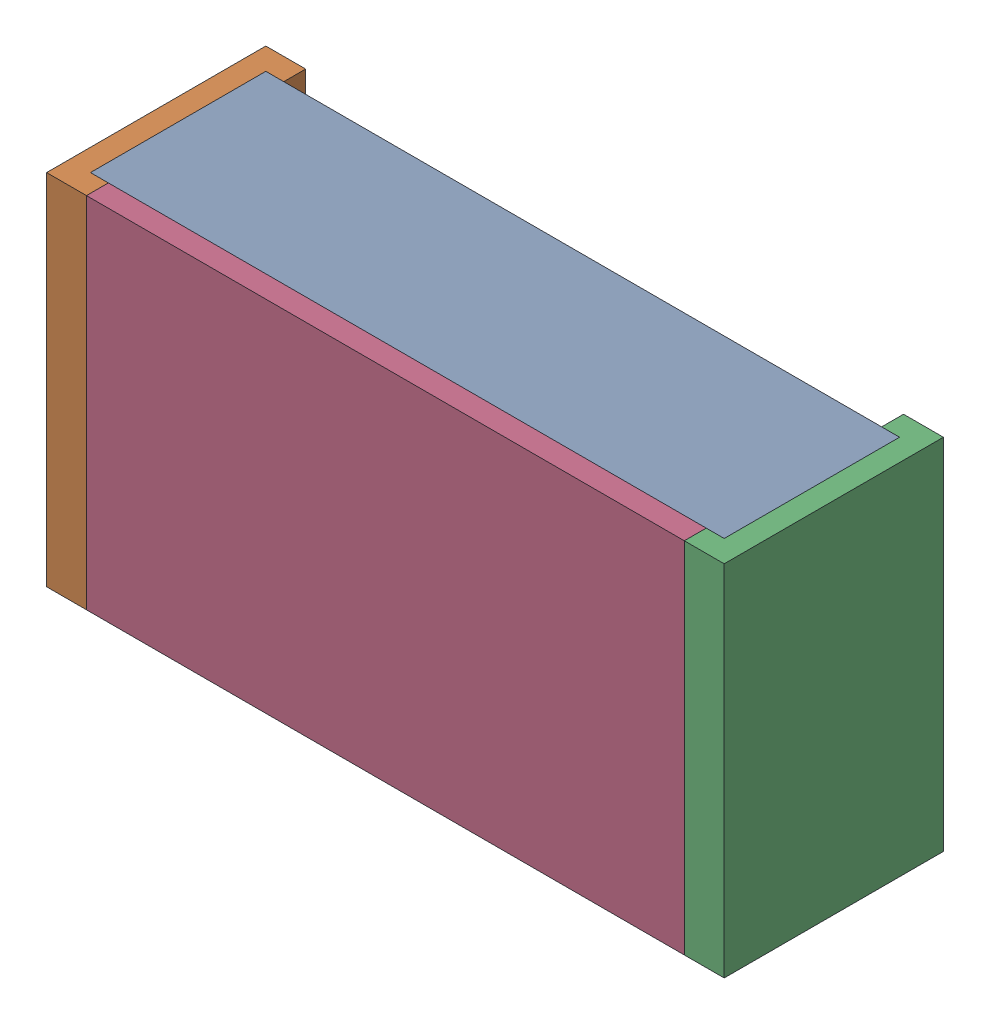
SolidWorks assembly 6152273536, configuration Default. Lengths in mm.
Overall size (1.7 0.9 0.55).
6 component instances, 3 part files, 0 mates.
Components (placement in the parent):
- Mid_Body_3-1: Mid_Body_3 [Default] at (-0.85 -0.45 0) size (1.59 0.9 0.44)
- Terminal_4-1: Terminal_4 [Default] at (-0.85 -0.45 0) size (0.1 0.9 0.55)
  - Open CASCADE STEP translator 6.8 15.2.1_3-1: Open CASCADE STEP translator 6.8 15.2.1_3 [Default] at origin size (0.1 0.9 0.55)
- Terminal_4-2: Terminal_4 [Default] at (0.85 0.45 0) x (-1 0 0) z (0 0 1) size (0.1 0.9 0.55)
  - Open CASCADE STEP translator 6.8 15.2.1_3-1: Open CASCADE STEP translator 6.8 15.2.1_3 [Default] at origin size (0.1 0.9 0.55)
- Mark_3-1: Mark_3 [Default] at (-0.75 -0.45 0.495) size (1.5 0.9 0.06)
